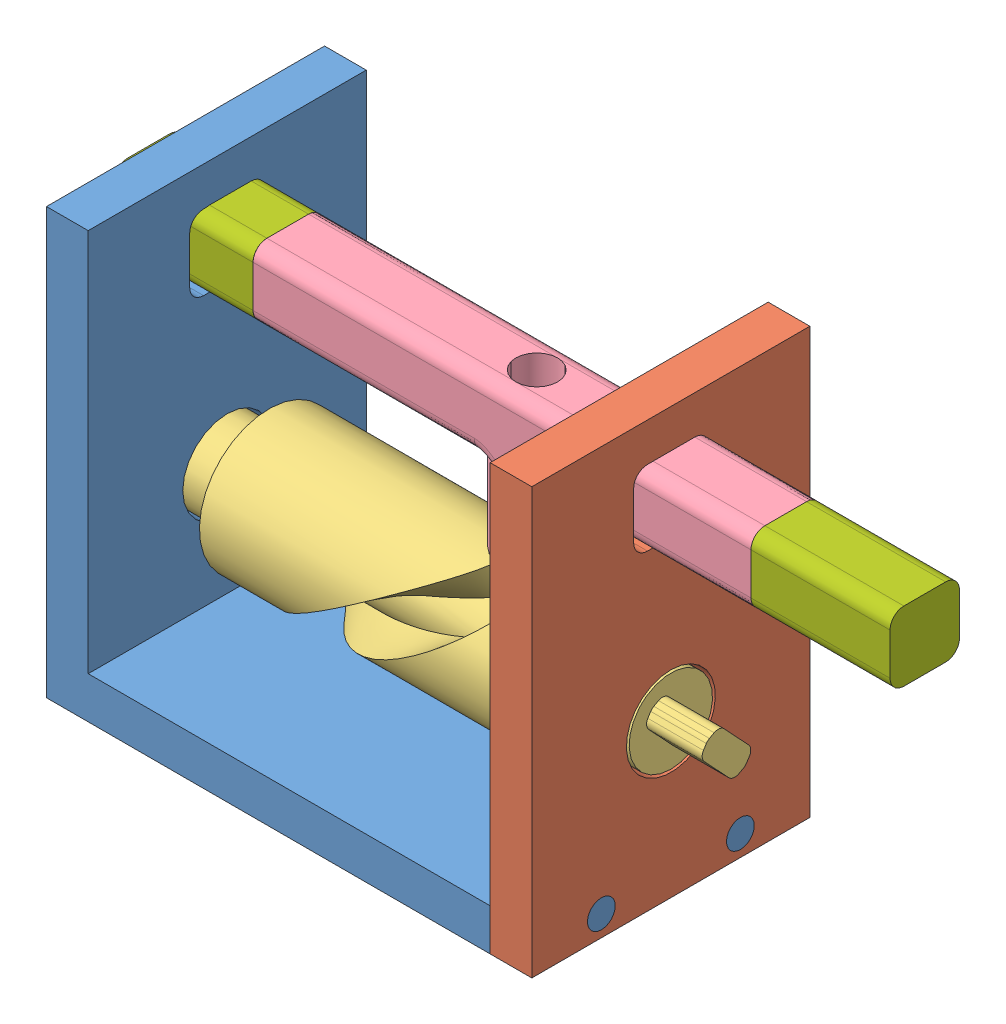
SolidWorks assembly montaj, configuration Varsayılan. Lengths in mm.
Overall size (279.08 153 100).
8 component instances, 7 part files, 19 mates.
Components (placement in the parent):
- iskelet1-1: iskelet1 [Varsayılan] at (95.162 -52.7456 178.2461) size (174.54 153 100)
- iskelet2-1: iskelet2 [Varsayılan] at (174.9319 23.7544 78.2461) size (15 153 100)
- gövde-1: gövde [Varsayılan] at (95.162 11.3928 136.7749) x (0 0.731073 0.682299) z (0 -0.682299 0.731073) size (50.06 187.04 50.06)
- hareketci-1: hareketci [Varsayılan] at (-6.4545 73.9081 127.1302) x (0 0 1) z (-1 0 0) size (25 55 179.08)
- needle roller bearing_nu_am-1: needle roller bearing_nu_am [AFBMA 18.1.3.6 - 16NU14 - Full,SI,NC,Full] at (133.0853 22.4081 127.1302) x (0 1 0) z (0.934878 0 -0.354968) size (12 16 16)
- continous stud_am-1: continous stud_am [AM -- M5 x 30  N] at (133.0853 16.4081 127.1302) x (0 1 0) z (0.157576 0 0.987507) size (30 5 5)
- hareketcieklenti-1: hareketcieklenti [Varsayılan] at (43.5455 73.9081 127.1302) x (0 0 1) z (-1 0 0) size (25 25 57.5)
- hareketcieklenti-2: hareketcieklenti [Varsayılan] at (222.6251 73.9081 127.1302) x (0 0 -1) z (1 0 0) size (25 25 57.5)
Mates (geometry in assembly coordinates):
- Eş Merkezli1: concentric: cylinder of iskelet1-1 through (182.4319 -45.2456 153.2461) axis (-1 0 0) radius 5; cylinder of iskelet2-1 through (167.4319 -45.2456 153.2461) axis (1 0 0) radius 5
- Çakışık1: coincident: plane of iskelet1-1 through (167.4319 -52.7456 78.2461) normal (1 0 0); plane of iskelet2-1 through (167.4319 100.2544 178.2461) normal (-1 0 0)
- Eş Merkezli2: concentric: cylinder of iskelet1-1 through (15.3921 2.2544 128.2461) axis (1 0 0) radius 16; cylinder of iskelet2-1 through (167.4319 2.2544 128.2461) axis (1 0 0) radius 16
- Eş Merkezli3: concentric: cylinder of iskelet2-1 through (167.4319 2.2544 128.2461) axis (1 0 0) radius 16; cylinder of gövde-1 through (182.4319 2.2544 128.2461) axis (-1 0 0) radius 15
- Çakışık2: coincident: plane of iskelet1-1 through (15.3921 2.2544 128.2461) normal (1 0 0); plane of gövde-1 through (15.3921 2.2544 128.2461) normal (-1 0 0)
- Eş Merkezli4: concentric: cylinder of needle roller bearing_nu_am-1 through (130.3466 14.4706 127.1302) axis (0 1 0) radius 2.5; cylinder of continous stud_am-1 through (130.3466 13.2331 127.1302) axis (0 -1 0) radius 2.5
- Çakışık3: coincident: plane of needle roller bearing_nu_am-1 through (132.63 16.4081 133.1438) normal (0 -1 0); plane of continous stud_am-1 through (127.8779 16.4081 127.5242) normal (0 -1 0)
- Eş Merkezli6: concentric: circle of hareketci-1; cylinder of continous stud_am-1 through (130.3466 13.2331 127.1302) axis (0 -1 0) radius 2.5
- Paralel2: parallel: plane of iskelet2-1 through (167.4319 64.4081 114.6302) normal (0 0 1); plane of hareketci-1 through (269.8865 86.4081 114.6302) normal (0 0 -1)
- Çakışık7: coincident: plane of iskelet2-1 through (167.4319 86.4081 136.6302) normal (0 -1 0); plane of hareketci-1 through (269.8865 86.4081 114.6302) normal (0 1 0)
- Paralel3: parallel: plane of iskelet1-1 through (7.8921 59.2544 136.7461) normal (0 1 0); plane of hareketci-1 through (269.8865 61.4081 114.6302) normal (0 -1 0)
- Çakışık12: coincident: plane of iskelet2-1 through (167.4319 64.4081 114.6302) normal (0 0 1); plane of hareketci-1 through (269.8865 86.4081 114.6302) normal (0 0 -1)
- Uzaklık1: distance = 3 mm: plane of needle roller bearing_nu_am-1 through (134.4235 28.4081 130.6547) normal (0 1 0); plane of hareketci-1 through (133.0853 31.4081 127.1302) normal (0 -1 0)
- Çakışık13: coincident: plane of hareketci-1 through (48.3068 72.1581 125.3802) normal (-1 0 0); plane of hareketcieklenti-1 through (48.3068 72.1581 128.8802) normal (1 0 0)
- Çakışık15: coincident: plane of hareketci-1 through (269.8865 86.4081 114.6302) normal (0 0 -1); plane of hareketcieklenti-1 through (-9.1932 81.4081 114.6302) normal (0 0 -1)
- Çakışık16: coincident: plane of hareketci-1 through (269.8865 86.4081 114.6302) normal (0 1 0); plane of hareketcieklenti-1 through (-9.1932 86.4081 119.6302) normal (0 1 0)
- Çakışık17: coincident: plane of hareketci-1 through (212.3865 72.1581 125.3802) normal (1 0 0); plane of hareketcieklenti-2 through (212.3865 72.1581 125.3802) normal (-1 0 0)
- Çakışık18: coincident: plane of hareketci-1 through (269.8865 86.4081 114.6302) normal (0 1 0); plane of hareketcieklenti-2 through (269.8865 86.4081 134.6302) normal (0 1 0)
- Çakışık19: coincident: plane of hareketci-1 through (269.8865 86.4081 114.6302) normal (0 0 -1); plane of hareketcieklenti-2 through (269.8865 81.4081 114.6302) normal (0 0 -1)
